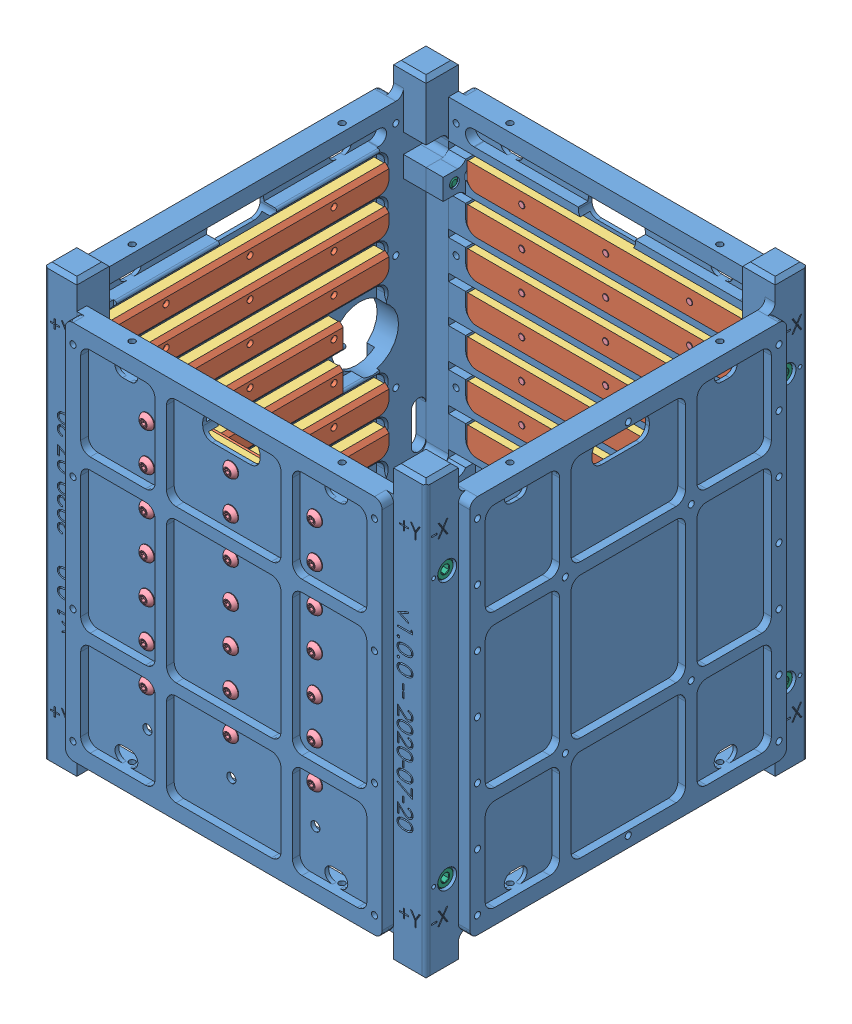
SolidWorks assembly 1UFrames, configuration Default. Lengths in mm.
Overall size (106 113.5 106).
137 component instances, 8 part files, 60 mates.
Components (placement in the parent):
- 1UFrame-2: 1UFrame [Y] at (0 0 50) x (-1 0 0) z (0 0 -1) size (83 99.5 11.5)
- 1UFrame-3: 1UFrame [+X] at (-50 0 0) x (0 0 -1) z (1 0 0) size (100 113.5 11.5)
- 1UFrame-4: 1UFrame [-X] at (50 0 0) x (0 0 1) z (-1 0 0) size (100 113.5 11.5)
- CardWedge-1: CardWedge [Default] at (0 34.95 47.1) x (-1 0 0) z (0 0 1) size (72.8 6.4 2)
- CardWedge-3: CardWedge [+Xframe] at (-47.1 34.95 0) x (0 0 -1) z (-1 0 0) size (72.8 5.9 3)
- CardWedgeTriangle-1: CardWedgeTriangle [Default] at (-50 37.35 0) x (0 -1 0) z (0 0 1) size (2 2.6 72.8)
- CardWedgeTriangle-2: CardWedgeTriangle [Default] at (0 37.85 50) x (0 -1 0) z (1 0 0) size (2 2.6 72.8)
- 90910A920_LOW-PROFILE BUTTON HEAD TORX MACHINE SCREW-1: 90910A920_LOW-PROFILE BUTTON HEAD TORX MACHINE SCREW [90910A920] at (-52.1 35.15 -22) x (0 0 1) z (-1 0 0) size (3.8 3.8 5.24)
- 90910A920_LOW-PROFILE BUTTON HEAD TORX MACHINE SCREW-73: 90910A920_LOW-PROFILE BUTTON HEAD TORX MACHINE SCREW [90910A920] at (-22 35.15 52.1) size (3.8 3.8 5.24)
- 93600A061_METRIC TYPE 316 STAINLESS STEEL DOWEL PIN-1: 93600A061_METRIC TYPE 316 STAINLESS STEEL DOWEL PIN [93600A061] at (41.5 33.95 -48) x (-1 0 0) z (0 0 -1) size (6 1.5 1.5)
- 93600A061_METRIC TYPE 316 STAINLESS STEEL DOWEL PIN-2: 93600A061_METRIC TYPE 316 STAINLESS STEEL DOWEL PIN [93600A061] at (41.5 -36.05 -48) size (6 1.5 1.5)
- 92290A060_TYPE 316 SS SOCKET HEAD CAP SCREW-1: 92290A060_TYPE 316 SS SOCKET HEAD CAP SCREW [92290A060] at (37 33.95 -44.45) x (0 0 1) z (-1 0 0) size (4.5 4.5 13.01)
- 92290A060_TYPE 316 SS SOCKET HEAD CAP SCREW-2: 92290A060_TYPE 316 SS SOCKET HEAD CAP SCREW [92290A060] at (37 -36.05 -44.45) x (0 0 1) z (-1 0 0) size (4.5 4.5 13.01)
- 84985A460_SHORT LENGTH SS LONG-NOSE SPRING PLUNGER-1: 84985A460_SHORT LENGTH SS LONG-NOSE SPRING PLUNGER [84985A46] at (45.75 -49.5999 -45.75) x (1 0 0) z (0 0 -1) size (4.81 12.73 4.27)
- 1UFrame-6: 1UFrame [Y] at (0 0 -50) size (83 99.5 11.5)
- 92290A060_TYPE 316 SS SOCKET HEAD CAP SCREW-3: 92290A060_TYPE 316 SS SOCKET HEAD CAP SCREW [92290A060] at (37 33.95 44.45) x (0 0 -1) z (-1 0 0) size (4.5 4.5 13.01)
- 93600A061_METRIC TYPE 316 STAINLESS STEEL DOWEL PIN-3: 93600A061_METRIC TYPE 316 STAINLESS STEEL DOWEL PIN [93600A061] at (41.5 33.95 48) x (-1 0 0) z (0 0 -1) size (6 1.5 1.5)
- 92290A060_TYPE 316 SS SOCKET HEAD CAP SCREW-4: 92290A060_TYPE 316 SS SOCKET HEAD CAP SCREW [92290A060] at (37 -36.05 44.45) x (0 0 -1) z (-1 0 0) size (4.5 4.5 13.01)
- 93600A061_METRIC TYPE 316 STAINLESS STEEL DOWEL PIN-4: 93600A061_METRIC TYPE 316 STAINLESS STEEL DOWEL PIN [93600A061] at (41.5 -36.05 48) size (6 1.5 1.5)
- 84985A460_SHORT LENGTH SS LONG-NOSE SPRING PLUNGER-3: 84985A460_SHORT LENGTH SS LONG-NOSE SPRING PLUNGER [84985A46] at (45.75 -49.5999 45.6569) x (1 0 0) z (0 0 -1) size (4.81 12.73 4.27)
- 92290A060_TYPE 316 SS SOCKET HEAD CAP SCREW-5: 92290A060_TYPE 316 SS SOCKET HEAD CAP SCREW [92290A060] at (-37 33.95 -44.45) x (0 0 1) z (1 0 0) size (4.5 4.5 13.01)
- 93600A061_METRIC TYPE 316 STAINLESS STEEL DOWEL PIN-5: 93600A061_METRIC TYPE 316 STAINLESS STEEL DOWEL PIN [93600A061] at (-41.5 33.95 -48) size (6 1.5 1.5)
- 92290A060_TYPE 316 SS SOCKET HEAD CAP SCREW-6: 92290A060_TYPE 316 SS SOCKET HEAD CAP SCREW [92290A060] at (-37 -36.05 -44.45) x (0 0 1) z (1 0 0) size (4.5 4.5 13.01)
- 93600A061_METRIC TYPE 316 STAINLESS STEEL DOWEL PIN-6: 93600A061_METRIC TYPE 316 STAINLESS STEEL DOWEL PIN [93600A061] at (-41.5 -36.05 -48) x (-1 0 0) z (0 0 -1) size (6 1.5 1.5)
- 84985A460_SHORT LENGTH SS LONG-NOSE SPRING PLUNGER-4: 84985A460_SHORT LENGTH SS LONG-NOSE SPRING PLUNGER [84985A46] at (-45.75 -49.5999 -45.6569) x (-1 0 0) z (0 0 1) size (4.81 12.73 4.27)
- 92290A060_TYPE 316 SS SOCKET HEAD CAP SCREW-7: 92290A060_TYPE 316 SS SOCKET HEAD CAP SCREW [92290A060] at (-37 33.95 44.45) x (0 0 -1) z (1 0 0) size (4.5 4.5 13.01)
- 93600A061_METRIC TYPE 316 STAINLESS STEEL DOWEL PIN-7: 93600A061_METRIC TYPE 316 STAINLESS STEEL DOWEL PIN [93600A061] at (-41.5 33.95 48) size (6 1.5 1.5)
- 92290A060_TYPE 316 SS SOCKET HEAD CAP SCREW-8: 92290A060_TYPE 316 SS SOCKET HEAD CAP SCREW [92290A060] at (-37 -36.05 44.45) x (0 0 -1) z (1 0 0) size (4.5 4.5 13.01)
- 93600A061_METRIC TYPE 316 STAINLESS STEEL DOWEL PIN-8: 93600A061_METRIC TYPE 316 STAINLESS STEEL DOWEL PIN [93600A061] at (-41.5 -36.05 48) x (-1 0 0) z (0 0 -1) size (6 1.5 1.5)
- 84985A460_SHORT LENGTH SS LONG-NOSE SPRING PLUNGER-5: 84985A460_SHORT LENGTH SS LONG-NOSE SPRING PLUNGER [84985A46] at (-45.75 -49.5999 45.75) x (-1 0 0) z (0 0 1) size (4.81 12.73 4.27)
- CardWedgeTriangle-3: CardWedgeTriangle [Default] at (0 27.85 50) x (0 -1 0) z (1 0 0) size (2 2.6 72.8)
- CardWedgeTriangle-4: CardWedgeTriangle [Default] at (0 17.85 50) x (0 -1 0) z (1 0 0) size (2 2.6 72.8)
- CardWedgeTriangle-5: CardWedgeTriangle [Default] at (0 7.85 50) x (0 -1 0) z (1 0 0) size (2 2.6 72.8)
- CardWedgeTriangle-6: CardWedgeTriangle [Default] at (0 -2.15 50) x (0 -1 0) z (1 0 0) size (2 2.6 72.8)
- CardWedgeTriangle-7: CardWedgeTriangle [Default] at (0 -12.15 50) x (0 -1 0) z (1 0 0) size (2 2.6 72.8)
- CardWedgeTriangle-8: CardWedgeTriangle [Default] at (0 -22.15 50) x (0 -1 0) z (1 0 0) size (2 2.6 72.8)
- CardWedge-4: CardWedge [Default] at (0 24.95 47.1) x (-1 0 0) z (0 0 1) size (72.8 6.4 2)
- CardWedge-5: CardWedge [Default] at (0 14.95 47.1) x (-1 0 0) z (0 0 1) size (72.8 6.4 2)
- CardWedge-6: CardWedge [Default] at (0 4.95 47.1) x (-1 0 0) z (0 0 1) size (72.8 6.4 2)
- CardWedge-7: CardWedge [Default] at (0 -5.05 47.1) x (-1 0 0) z (0 0 1) size (72.8 6.4 2)
- CardWedge-8: CardWedge [Default] at (0 -15.05 47.1) x (-1 0 0) z (0 0 1) size (72.8 6.4 2)
- CardWedge-9: CardWedge [Default] at (0 -25.05 47.1) x (-1 0 0) z (0 0 1) size (72.8 6.4 2)
- 90910A920_LOW-PROFILE BUTTON HEAD TORX MACHINE SCREW-74: 90910A920_LOW-PROFILE BUTTON HEAD TORX MACHINE SCREW [90910A920] at (-22 25.15 52.1) size (3.8 3.8 5.24)
- 90910A920_LOW-PROFILE BUTTON HEAD TORX MACHINE SCREW-75: 90910A920_LOW-PROFILE BUTTON HEAD TORX MACHINE SCREW [90910A920] at (-22 15.15 52.1) size (3.8 3.8 5.24)
- 90910A920_LOW-PROFILE BUTTON HEAD TORX MACHINE SCREW-76: 90910A920_LOW-PROFILE BUTTON HEAD TORX MACHINE SCREW [90910A920] at (-22 5.15 52.1) size (3.8 3.8 5.24)
- 90910A920_LOW-PROFILE BUTTON HEAD TORX MACHINE SCREW-77: 90910A920_LOW-PROFILE BUTTON HEAD TORX MACHINE SCREW [90910A920] at (-22 -4.85 52.1) size (3.8 3.8 5.24)
- 90910A920_LOW-PROFILE BUTTON HEAD TORX MACHINE SCREW-78: 90910A920_LOW-PROFILE BUTTON HEAD TORX MACHINE SCREW [90910A920] at (-22 -14.85 52.1) size (3.8 3.8 5.24)
- 90910A920_LOW-PROFILE BUTTON HEAD TORX MACHINE SCREW-79: 90910A920_LOW-PROFILE BUTTON HEAD TORX MACHINE SCREW [90910A920] at (-22 -24.85 52.1) size (3.8 3.8 5.24)
- 90910A920_LOW-PROFILE BUTTON HEAD TORX MACHINE SCREW-81: 90910A920_LOW-PROFILE BUTTON HEAD TORX MACHINE SCREW [90910A920] at (0 35.15 52.1) size (3.8 3.8 5.24)
- 90910A920_LOW-PROFILE BUTTON HEAD TORX MACHINE SCREW-82: 90910A920_LOW-PROFILE BUTTON HEAD TORX MACHINE SCREW [90910A920] at (0 25.15 52.1) size (3.8 3.8 5.24)
- 90910A920_LOW-PROFILE BUTTON HEAD TORX MACHINE SCREW-83: 90910A920_LOW-PROFILE BUTTON HEAD TORX MACHINE SCREW [90910A920] at (0 15.15 52.1) size (3.8 3.8 5.24)
- 90910A920_LOW-PROFILE BUTTON HEAD TORX MACHINE SCREW-84: 90910A920_LOW-PROFILE BUTTON HEAD TORX MACHINE SCREW [90910A920] at (0 5.15 52.1) size (3.8 3.8 5.24)
- 90910A920_LOW-PROFILE BUTTON HEAD TORX MACHINE SCREW-85: 90910A920_LOW-PROFILE BUTTON HEAD TORX MACHINE SCREW [90910A920] at (0 -4.85 52.1) size (3.8 3.8 5.24)
- 90910A920_LOW-PROFILE BUTTON HEAD TORX MACHINE SCREW-86: 90910A920_LOW-PROFILE BUTTON HEAD TORX MACHINE SCREW [90910A920] at (0 -14.85 52.1) size (3.8 3.8 5.24)
- 90910A920_LOW-PROFILE BUTTON HEAD TORX MACHINE SCREW-87: 90910A920_LOW-PROFILE BUTTON HEAD TORX MACHINE SCREW [90910A920] at (0 -24.85 52.1) size (3.8 3.8 5.24)
- 90910A920_LOW-PROFILE BUTTON HEAD TORX MACHINE SCREW-89: 90910A920_LOW-PROFILE BUTTON HEAD TORX MACHINE SCREW [90910A920] at (22 35.15 52.1) size (3.8 3.8 5.24)
- 90910A920_LOW-PROFILE BUTTON HEAD TORX MACHINE SCREW-90: 90910A920_LOW-PROFILE BUTTON HEAD TORX MACHINE SCREW [90910A920] at (22 25.15 52.1) size (3.8 3.8 5.24)
- 90910A920_LOW-PROFILE BUTTON HEAD TORX MACHINE SCREW-91: 90910A920_LOW-PROFILE BUTTON HEAD TORX MACHINE SCREW [90910A920] at (22 15.15 52.1) size (3.8 3.8 5.24)
- 90910A920_LOW-PROFILE BUTTON HEAD TORX MACHINE SCREW-92: 90910A920_LOW-PROFILE BUTTON HEAD TORX MACHINE SCREW [90910A920] at (22 5.15 52.1) size (3.8 3.8 5.24)
- 90910A920_LOW-PROFILE BUTTON HEAD TORX MACHINE SCREW-93: 90910A920_LOW-PROFILE BUTTON HEAD TORX MACHINE SCREW [90910A920] at (22 -4.85 52.1) size (3.8 3.8 5.24)
- 90910A920_LOW-PROFILE BUTTON HEAD TORX MACHINE SCREW-94: 90910A920_LOW-PROFILE BUTTON HEAD TORX MACHINE SCREW [90910A920] at (22 -14.85 52.1) size (3.8 3.8 5.24)
- 90910A920_LOW-PROFILE BUTTON HEAD TORX MACHINE SCREW-95: 90910A920_LOW-PROFILE BUTTON HEAD TORX MACHINE SCREW [90910A920] at (22 -24.85 52.1) size (3.8 3.8 5.24)
- CardWedgeTriangle-10: CardWedgeTriangle [Default] at (0 37.85 -50) x (0 -1 0) z (-1 0 0) size (2 2.6 72.8)
- CardWedge-11: CardWedge [Default] at (0 34.95 -47.1) x (1 0 0) z (0 0 -1) size (72.8 6.4 2)
- CardWedgeTriangle-11: CardWedgeTriangle [Default] at (0 27.85 -50) x (0 -1 0) z (-1 0 0) size (2 2.6 72.8)
- CardWedgeTriangle-12: CardWedgeTriangle [Default] at (0 17.85 -50) x (0 -1 0) z (-1 0 0) size (2 2.6 72.8)
- CardWedgeTriangle-13: CardWedgeTriangle [Default] at (0 7.85 -50) x (0 -1 0) z (-1 0 0) size (2 2.6 72.8)
- CardWedgeTriangle-14: CardWedgeTriangle [Default] at (0 -2.15 -50) x (0 -1 0) z (-1 0 0) size (2 2.6 72.8)
- CardWedgeTriangle-15: CardWedgeTriangle [Default] at (0 -12.15 -50) x (0 -1 0) z (-1 0 0) size (2 2.6 72.8)
- CardWedgeTriangle-16: CardWedgeTriangle [Default] at (0 -22.15 -50) x (0 -1 0) z (-1 0 0) size (2 2.6 72.8)
- CardWedge-12: CardWedge [Default] at (0 24.95 -47.1) x (1 0 0) z (0 0 -1) size (72.8 6.4 2)
- CardWedge-13: CardWedge [Default] at (0 14.95 -47.1) x (1 0 0) z (0 0 -1) size (72.8 6.4 2)
- CardWedge-14: CardWedge [Default] at (0 4.95 -47.1) x (1 0 0) z (0 0 -1) size (72.8 6.4 2)
- CardWedge-15: CardWedge [Default] at (0 -5.05 -47.1) x (1 0 0) z (0 0 -1) size (72.8 6.4 2)
- CardWedge-16: CardWedge [Default] at (0 -15.05 -47.1) x (1 0 0) z (0 0 -1) size (72.8 6.4 2)
- CardWedge-17: CardWedge [Default] at (0 -25.05 -47.1) x (1 0 0) z (0 0 -1) size (72.8 6.4 2)
- 90910A920_LOW-PROFILE BUTTON HEAD TORX MACHINE SCREW-97: 90910A920_LOW-PROFILE BUTTON HEAD TORX MACHINE SCREW [90910A920] at (-22 35.15 -52.1) x (1 0 0) z (0 0 -1) size (3.8 3.8 5.24)
- 90910A920_LOW-PROFILE BUTTON HEAD TORX MACHINE SCREW-98: 90910A920_LOW-PROFILE BUTTON HEAD TORX MACHINE SCREW [90910A920] at (-22 25.15 -52.1) x (1 0 0) z (0 0 -1) size (3.8 3.8 5.24)
- 90910A920_LOW-PROFILE BUTTON HEAD TORX MACHINE SCREW-99: 90910A920_LOW-PROFILE BUTTON HEAD TORX MACHINE SCREW [90910A920] at (-22 15.15 -52.1) x (1 0 0) z (0 0 -1) size (3.8 3.8 5.24)
- 90910A920_LOW-PROFILE BUTTON HEAD TORX MACHINE SCREW-100: 90910A920_LOW-PROFILE BUTTON HEAD TORX MACHINE SCREW [90910A920] at (-22 5.15 -52.1) x (1 0 0) z (0 0 -1) size (3.8 3.8 5.24)
- 90910A920_LOW-PROFILE BUTTON HEAD TORX MACHINE SCREW-101: 90910A920_LOW-PROFILE BUTTON HEAD TORX MACHINE SCREW [90910A920] at (-22 -4.85 -52.1) x (1 0 0) z (0 0 -1) size (3.8 3.8 5.24)
- 90910A920_LOW-PROFILE BUTTON HEAD TORX MACHINE SCREW-102: 90910A920_LOW-PROFILE BUTTON HEAD TORX MACHINE SCREW [90910A920] at (-22 -14.85 -52.1) x (1 0 0) z (0 0 -1) size (3.8 3.8 5.24)
- 90910A920_LOW-PROFILE BUTTON HEAD TORX MACHINE SCREW-103: 90910A920_LOW-PROFILE BUTTON HEAD TORX MACHINE SCREW [90910A920] at (-22 -24.85 -52.1) x (1 0 0) z (0 0 -1) size (3.8 3.8 5.24)
- 90910A920_LOW-PROFILE BUTTON HEAD TORX MACHINE SCREW-104: 90910A920_LOW-PROFILE BUTTON HEAD TORX MACHINE SCREW [90910A920] at (0 35.15 -52.1) x (1 0 0) z (0 0 -1) size (3.8 3.8 5.24)
- 90910A920_LOW-PROFILE BUTTON HEAD TORX MACHINE SCREW-105: 90910A920_LOW-PROFILE BUTTON HEAD TORX MACHINE SCREW [90910A920] at (0 25.15 -52.1) x (1 0 0) z (0 0 -1) size (3.8 3.8 5.24)
- 90910A920_LOW-PROFILE BUTTON HEAD TORX MACHINE SCREW-106: 90910A920_LOW-PROFILE BUTTON HEAD TORX MACHINE SCREW [90910A920] at (0 15.15 -52.1) x (1 0 0) z (0 0 -1) size (3.8 3.8 5.24)
- 90910A920_LOW-PROFILE BUTTON HEAD TORX MACHINE SCREW-107: 90910A920_LOW-PROFILE BUTTON HEAD TORX MACHINE SCREW [90910A920] at (0 5.15 -52.1) x (1 0 0) z (0 0 -1) size (3.8 3.8 5.24)
- 90910A920_LOW-PROFILE BUTTON HEAD TORX MACHINE SCREW-108: 90910A920_LOW-PROFILE BUTTON HEAD TORX MACHINE SCREW [90910A920] at (0 -4.85 -52.1) x (1 0 0) z (0 0 -1) size (3.8 3.8 5.24)
- 90910A920_LOW-PROFILE BUTTON HEAD TORX MACHINE SCREW-109: 90910A920_LOW-PROFILE BUTTON HEAD TORX MACHINE SCREW [90910A920] at (0 -14.85 -52.1) x (1 0 0) z (0 0 -1) size (3.8 3.8 5.24)
- 90910A920_LOW-PROFILE BUTTON HEAD TORX MACHINE SCREW-110: 90910A920_LOW-PROFILE BUTTON HEAD TORX MACHINE SCREW [90910A920] at (0 -24.85 -52.1) x (1 0 0) z (0 0 -1) size (3.8 3.8 5.24)
- 90910A920_LOW-PROFILE BUTTON HEAD TORX MACHINE SCREW-111: 90910A920_LOW-PROFILE BUTTON HEAD TORX MACHINE SCREW [90910A920] at (22 35.15 -52.1) x (1 0 0) z (0 0 -1) size (3.8 3.8 5.24)
- 90910A920_LOW-PROFILE BUTTON HEAD TORX MACHINE SCREW-112: 90910A920_LOW-PROFILE BUTTON HEAD TORX MACHINE SCREW [90910A920] at (22 25.15 -52.1) x (1 0 0) z (0 0 -1) size (3.8 3.8 5.24)
- 90910A920_LOW-PROFILE BUTTON HEAD TORX MACHINE SCREW-113: 90910A920_LOW-PROFILE BUTTON HEAD TORX MACHINE SCREW [90910A920] at (22 15.15 -52.1) x (1 0 0) z (0 0 -1) size (3.8 3.8 5.24)
- 90910A920_LOW-PROFILE BUTTON HEAD TORX MACHINE SCREW-114: 90910A920_LOW-PROFILE BUTTON HEAD TORX MACHINE SCREW [90910A920] at (22 5.15 -52.1) x (1 0 0) z (0 0 -1) size (3.8 3.8 5.24)
- 90910A920_LOW-PROFILE BUTTON HEAD TORX MACHINE SCREW-115: 90910A920_LOW-PROFILE BUTTON HEAD TORX MACHINE SCREW [90910A920] at (22 -4.85 -52.1) x (1 0 0) z (0 0 -1) size (3.8 3.8 5.24)
- 90910A920_LOW-PROFILE BUTTON HEAD TORX MACHINE SCREW-116: 90910A920_LOW-PROFILE BUTTON HEAD TORX MACHINE SCREW [90910A920] at (22 -14.85 -52.1) x (1 0 0) z (0 0 -1) size (3.8 3.8 5.24)
- 90910A920_LOW-PROFILE BUTTON HEAD TORX MACHINE SCREW-117: 90910A920_LOW-PROFILE BUTTON HEAD TORX MACHINE SCREW [90910A920] at (22 -24.85 -52.1) x (1 0 0) z (0 0 -1) size (3.8 3.8 5.24)
- CardWedge-19: CardWedge [+Xframe] at (-47.1 24.95 0) x (0 0 -1) z (-1 0 0) size (72.8 5.9 3)
- CardWedge-20: CardWedge [+Xframe] at (-47.1 14.95 0) x (0 0 -1) z (-1 0 0) size (72.8 5.9 3)
- CardWedge-23: CardWedge [+Xframe] at (-47.1 -15.05 0) x (0 0 -1) z (-1 0 0) size (72.8 5.9 3)
- CardWedge-24: CardWedge [+Xframe] at (-47.1 -25.05 0) x (0 0 -1) z (-1 0 0) size (72.8 5.9 3)
- CardWedgeTriangle-18: CardWedgeTriangle [Default] at (-50 27.35 0) x (0 -1 0) z (0 0 1) size (2 2.6 72.8)
- CardWedgeTriangle-19: CardWedgeTriangle [Default] at (-50 17.35 0) x (0 -1 0) z (0 0 1) size (2 2.6 72.8)
- CardWedgeTriangle-22: CardWedgeTriangle [Default] at (-50 -12.65 0) x (0 -1 0) z (0 0 1) size (2 2.6 72.8)
- CardWedgeTriangle-23: CardWedgeTriangle [Default] at (-50 -22.65 0) x (0 -1 0) z (0 0 1) size (2 2.6 72.8)
- 90910A920_LOW-PROFILE BUTTON HEAD TORX MACHINE SCREW-50: 90910A920_LOW-PROFILE BUTTON HEAD TORX MACHINE SCREW [90910A920] at (-52.1 25.15 -22) x (0 0 1) z (-1 0 0) size (3.8 3.8 5.24)
- 90910A920_LOW-PROFILE BUTTON HEAD TORX MACHINE SCREW-51: 90910A920_LOW-PROFILE BUTTON HEAD TORX MACHINE SCREW [90910A920] at (-52.1 15.15 -22) x (0 0 1) z (-1 0 0) size (3.8 3.8 5.24)
- 90910A920_LOW-PROFILE BUTTON HEAD TORX MACHINE SCREW-52: 90910A920_LOW-PROFILE BUTTON HEAD TORX MACHINE SCREW [90910A920] at (-52.1 5.15 -22) x (0 0 1) z (-1 0 0) size (3.8 3.8 5.24)
- 90910A920_LOW-PROFILE BUTTON HEAD TORX MACHINE SCREW-53: 90910A920_LOW-PROFILE BUTTON HEAD TORX MACHINE SCREW [90910A920] at (-52.1 -4.85 -22) x (0 0 1) z (-1 0 0) size (3.8 3.8 5.24)
- 90910A920_LOW-PROFILE BUTTON HEAD TORX MACHINE SCREW-54: 90910A920_LOW-PROFILE BUTTON HEAD TORX MACHINE SCREW [90910A920] at (-52.1 -14.85 -22) x (0 0 1) z (-1 0 0) size (3.8 3.8 5.24)
- 90910A920_LOW-PROFILE BUTTON HEAD TORX MACHINE SCREW-55: 90910A920_LOW-PROFILE BUTTON HEAD TORX MACHINE SCREW [90910A920] at (-52.1 -24.85 -22) x (0 0 1) z (-1 0 0) size (3.8 3.8 5.24)
- 90910A920_LOW-PROFILE BUTTON HEAD TORX MACHINE SCREW-57: 90910A920_LOW-PROFILE BUTTON HEAD TORX MACHINE SCREW [90910A920] at (-52.1 35.15 0) x (0 0 1) z (-1 0 0) size (3.8 3.8 5.24)
- 90910A920_LOW-PROFILE BUTTON HEAD TORX MACHINE SCREW-58: 90910A920_LOW-PROFILE BUTTON HEAD TORX MACHINE SCREW [90910A920] at (-52.1 25.15 0) x (0 0 1) z (-1 0 0) size (3.8 3.8 5.24)
- 90910A920_LOW-PROFILE BUTTON HEAD TORX MACHINE SCREW-59: 90910A920_LOW-PROFILE BUTTON HEAD TORX MACHINE SCREW [90910A920] at (-52.1 15.15 0) x (0 0 1) z (-1 0 0) size (3.8 3.8 5.24)
- 90910A920_LOW-PROFILE BUTTON HEAD TORX MACHINE SCREW-60: 90910A920_LOW-PROFILE BUTTON HEAD TORX MACHINE SCREW [90910A920] at (-52.1 5.15 0) x (0 0 1) z (-1 0 0) size (3.8 3.8 5.24)
- 90910A920_LOW-PROFILE BUTTON HEAD TORX MACHINE SCREW-61: 90910A920_LOW-PROFILE BUTTON HEAD TORX MACHINE SCREW [90910A920] at (-52.1 -4.85 0) x (0 0 1) z (-1 0 0) size (3.8 3.8 5.24)
- 90910A920_LOW-PROFILE BUTTON HEAD TORX MACHINE SCREW-62: 90910A920_LOW-PROFILE BUTTON HEAD TORX MACHINE SCREW [90910A920] at (-52.1 -14.85 0) x (0 0 1) z (-1 0 0) size (3.8 3.8 5.24)
- 90910A920_LOW-PROFILE BUTTON HEAD TORX MACHINE SCREW-63: 90910A920_LOW-PROFILE BUTTON HEAD TORX MACHINE SCREW [90910A920] at (-52.1 -24.85 0) x (0 0 1) z (-1 0 0) size (3.8 3.8 5.24)
- 90910A920_LOW-PROFILE BUTTON HEAD TORX MACHINE SCREW-65: 90910A920_LOW-PROFILE BUTTON HEAD TORX MACHINE SCREW [90910A920] at (-52.1 35.15 22) x (0 0 1) z (-1 0 0) size (3.8 3.8 5.24)
- 90910A920_LOW-PROFILE BUTTON HEAD TORX MACHINE SCREW-66: 90910A920_LOW-PROFILE BUTTON HEAD TORX MACHINE SCREW [90910A920] at (-52.1 25.15 22) x (0 0 1) z (-1 0 0) size (3.8 3.8 5.24)
- 90910A920_LOW-PROFILE BUTTON HEAD TORX MACHINE SCREW-67: 90910A920_LOW-PROFILE BUTTON HEAD TORX MACHINE SCREW [90910A920] at (-52.1 15.15 22) x (0 0 1) z (-1 0 0) size (3.8 3.8 5.24)
- 90910A920_LOW-PROFILE BUTTON HEAD TORX MACHINE SCREW-68: 90910A920_LOW-PROFILE BUTTON HEAD TORX MACHINE SCREW [90910A920] at (-52.1 5.15 22) x (0 0 1) z (-1 0 0) size (3.8 3.8 5.24)
- 90910A920_LOW-PROFILE BUTTON HEAD TORX MACHINE SCREW-69: 90910A920_LOW-PROFILE BUTTON HEAD TORX MACHINE SCREW [90910A920] at (-52.1 -4.85 22) x (0 0 1) z (-1 0 0) size (3.8 3.8 5.24)
- 90910A920_LOW-PROFILE BUTTON HEAD TORX MACHINE SCREW-70: 90910A920_LOW-PROFILE BUTTON HEAD TORX MACHINE SCREW [90910A920] at (-52.1 -14.85 22) x (0 0 1) z (-1 0 0) size (3.8 3.8 5.24)
- 90910A920_LOW-PROFILE BUTTON HEAD TORX MACHINE SCREW-71: 90910A920_LOW-PROFILE BUTTON HEAD TORX MACHINE SCREW [90910A920] at (-52.1 -24.85 22) x (0 0 1) z (-1 0 0) size (3.8 3.8 5.24)
- CardWedgeTriangle-25: CardWedgeTriangle [StarTrackerWedge] at (-50 7.35 0) x (0 -1 0) z (0 0 1) size (2 2.6 60.8)
- CardWedge-26: CardWedge [startrackerwedge] at (-47.1 4.95 0) x (0 0 -1) z (-1 0 0) size (60.8 5.9 3)
- CardWedgeTriangle-26: CardWedgeTriangle [StarTrackerWedge] at (-50 -2.65 0) x (0 -1 0) z (0 0 1) size (2 2.6 60.8)
- CardWedge-27: CardWedge [startrackerwedge] at (-47.1 -5.05 0) x (0 0 -1) z (-1 0 0) size (60.8 5.9 3)
- 91630A221_SCREW-LOCK HELICAL INSERTS WITHOUT PRONG-1: 91630A221_SCREW-LOCK HELICAL INSERTS WITHOUT PRONG [91630A221] at (41.5 33.95 -44.45) x (0 1 0) z (0 0 1) size (3.78 2.46 4.27)
- 91630A221_SCREW-LOCK HELICAL INSERTS WITHOUT PRONG-2: 91630A221_SCREW-LOCK HELICAL INSERTS WITHOUT PRONG [91630A221] at (41.5 -36.05 -44.45) x (0 1 0) z (0 0 1) size (3.78 2.46 4.27)
- 91630A221_SCREW-LOCK HELICAL INSERTS WITHOUT PRONG-3: 91630A221_SCREW-LOCK HELICAL INSERTS WITHOUT PRONG [91630A221] at (41.5 33.95 44.45) x (0 1 0) z (0 0 1) size (3.78 2.46 4.27)
- 91630A221_SCREW-LOCK HELICAL INSERTS WITHOUT PRONG-4: 91630A221_SCREW-LOCK HELICAL INSERTS WITHOUT PRONG [91630A221] at (41.5 -36.05 44.45) x (0 1 0) z (0 0 1) size (3.78 2.46 4.27)
- 91630A221_SCREW-LOCK HELICAL INSERTS WITHOUT PRONG-5: 91630A221_SCREW-LOCK HELICAL INSERTS WITHOUT PRONG [91630A221] at (-41.5 33.95 44.45) x (0 1 0) z (0 0 -1) size (3.78 2.46 4.27)
- 91630A221_SCREW-LOCK HELICAL INSERTS WITHOUT PRONG-6: 91630A221_SCREW-LOCK HELICAL INSERTS WITHOUT PRONG [91630A221] at (-41.5 -36.05 44.45) x (0 1 0) z (0 0 -1) size (3.78 2.46 4.27)
- 91630A221_SCREW-LOCK HELICAL INSERTS WITHOUT PRONG-7: 91630A221_SCREW-LOCK HELICAL INSERTS WITHOUT PRONG [91630A221] at (-41.5 -36.05 -44.45) x (0 1 0) z (0 0 -1) size (3.78 2.46 4.27)
- 91630A221_SCREW-LOCK HELICAL INSERTS WITHOUT PRONG-8: 91630A221_SCREW-LOCK HELICAL INSERTS WITHOUT PRONG [91630A221] at (-41.5 33.95 -44.45) x (0 1 0) z (0 0 -1) size (3.78 2.46 4.27)
Mates (geometry in assembly coordinates):
- Coincident2: coincident anti-aligned: plane of 1UFrame-2 through (41.5 0 47.4) normal (1 0 0); plane of 1UFrame-4 through (41.5 0 0) normal (-1 0 0)
- Concentric2: concentric aligned: cylinder of 1UFrame-2 through (41.5 33.95 44.45) axis (1 0 0) radius 1.275; cylinder of 1UFrame-4 through (47 33.95 44.45) axis (1 0 0) radius 1.45
- Coincident30: coincident aligned: plane of 1UFrame-4 through (50 0 0) normal (0 0 1)
- Parallel2: parallel anti-aligned: plane of 1UFrame-2 through (0 0 50) normal (0 0 -1)
- Coincident6: coincident anti-aligned: plane of 1UFrame-2 through (-41.5 0 47.4) normal (-1 0 0); plane of 1UFrame-3 through (-41.5 0 0) normal (1 0 0)
- Concentric3: concentric aligned: cylinder of 1UFrame-2 through (-41.5 33.95 44.45) axis (-1 0 0) radius 1.275; cylinder of 1UFrame-3 through (-47 33.95 44.45) axis (-1 0 0) radius 1.45
- Coincident7: coincident aligned: plane of 1UFrame-2 through (0 0 50) normal (0 1 0)
- Coincident8: coincident anti-aligned: plane of 1UFrame-2 through (0 0 50) normal (-1 0 0)
- Coincident9: coincident anti-aligned: plane of 1UFrame-3 through (-50 0 0) normal (0 0 -1)
- Coincident10: coincident aligned: plane of 1UFrame-5 through (0 0 -50) normal (0 1 0)
- Coincident11: coincident aligned: plane of 1UFrame-5 through (0 0 -50) normal (1 0 0)
- Concentric4: concentric aligned: cylinder of 1UFrame-3 through (-47 33.95 -44.45) axis (-1 0 0) radius 1.45; cylinder of 1UFrame-5 through (-41.5 33.95 -44.45) axis (-1 0 0) radius 1.275
- Coincident12: coincident anti-aligned: plane of 1UFrame-3 through (26.627 31.75 37) normal (0 1 0); plane of CardWedge-3 through (-49.1 31.75 -36.4) normal (0 -1 0)
- Concentric5: concentric aligned: cylinder of 1UFrame-3 through (-51 35.15 0) axis (-1 0 0) radius 1.2; cylinder of CardWedge-3 through (-49.1 35.15 0) axis (-1 0 0) radius 0.8
- Coincident14: coincident anti-aligned: plane of 1UFrame-3 through (-50 0 0) normal (1 0 0); plane of CardWedgeTriangle-1 through (-50 37.35 -36.4) normal (-1 0 0)
- Coincident15: coincident anti-aligned: plane of CardWedgeTriangle-1 through (-48.7 36.05 -36.4) normal (0.707107 -0.707107 0); plane of CardWedge-3 through (-47.1 37.65 -39.6016) normal (-0.707107 0.707107 0)
- Coincident17: coincident aligned: plane of CardWedgeTriangle-1 through (-50 37.35 36.4) normal (0 0 1); plane of CardWedge-3 through (-47.1 34.95 36.4) normal (0 0 1)
- Coincident18: coincident anti-aligned: plane of 1UFrame-3 through (-51 0 0) normal (-1 0 0); plane of 92095A104_BUTTON HEAD HEX DRIVE SCREW-3 through (-51 35.15 -20.1) normal (1 0 0)
- Concentric7: concentric aligned: circle of 1UFrame-3; circle of 92095A104_BUTTON HEAD HEX DRIVE SCREW-3
- Parallel4: parallel anti-aligned: plane of 92095A104_BUTTON HEAD HEX DRIVE SCREW-3 through (-51.9 35.15 -22) normal (0 0 -1)
- Coincident20: coincident anti-aligned: plane of 1UFrame-2 through (37 31.75 -26.627) normal (0 1 0); plane of CardWedge-1 through (-36.4 31.75 49.1) normal (0 -1 0)
- Concentric8: concentric aligned: cylinder of 1UFrame-2 through (0 35.15 51) axis (0 0 1) radius 1.2; cylinder of CardWedge-1 through (0 35.15 49.1) axis (0 0 1) radius 0.8
- Coincident24: coincident anti-aligned: plane of 1UFrame-2 through (0 0 50) normal (0 0 -1); plane of CardWedgeTriangle-2 through (-36.4 37.85 50) normal (0 0 1)
- Coincident25: coincident anti-aligned: plane of CardWedge-1 through (-36.4 38.15 47.1) normal (0 0.707107 0.707107); plane of CardWedgeTriangle-2 through (-36.4 36.55 48.7) normal (0 -0.707107 -0.707107)
- Concentric11: concentric aligned: cylinder of 1UFrame-3 through (-51 35.15 0) axis (-1 0 0) radius 1.2; cylinder of CardWedgeTriangle-1 through (-45.8444 35.15 0) axis (-1 0 0) radius 1.1
- Coincident26: coincident aligned: plane of 1UFrame-2 through (41.5 37.85 50) normal (0 1 0); plane of CardWedgeTriangle-2 through (-36.4 37.85 50) normal (0 1 0)
- Coincident31: coincident anti-aligned: plane of 1UFrame-3 through (-51 0 0) normal (-1 0 0); plane of 90910A920_LOW-PROFILE BUTTON HEAD TORX MACHINE SCREW-1 through (-51 33.25 -22) normal (1 0 0)
- Concentric14: concentric aligned: cylinder of 1UFrame-3 through (-51 35.15 -22) axis (-1 0 0) radius 1.2; cylinder of 90910A920_LOW-PROFILE BUTTON HEAD TORX MACHINE SCREW-1 through (-52.1 35.15 -22) axis (-1 0 0) radius 1.9
- Coincident32: coincident anti-aligned: plane of 1UFrame-2 through (0 0 51) normal (0 0 1); plane of 90910A920_LOW-PROFILE BUTTON HEAD TORX MACHINE SCREW-73 through (-22 33.25 51) normal (0 0 -1)
- Concentric15: concentric aligned: cylinder of 1UFrame-2 through (-22 35.15 51) axis (0 0 1) radius 1.2; cylinder of 90910A920_LOW-PROFILE BUTTON HEAD TORX MACHINE SCREW-73 through (-22 35.15 52.1) axis (0 0 1) radius 1.9
- Parallel5: parallel aligned: plane of 90910A920_LOW-PROFILE BUTTON HEAD TORX MACHINE SCREW-1 through (-52.1 35.15 -22) normal (0 0 1)
- Parallel6: parallel aligned: plane of 90910A920_LOW-PROFILE BUTTON HEAD TORX MACHINE SCREW-73 through (-22 35.15 52.1) normal (1 0 0)
- Concentric18: concentric aligned: cone of 1UFrame-4 through (44.5 33.95 -48) axis (1 0 0); cone of 93600A061_METRIC TYPE 316 STAINLESS STEEL DOWEL PIN-1 through (44.2 33.95 -48) axis (1 0 0)
- Coincident36: coincident anti-aligned: circle of 1UFrame-4; plane of 93600A061_METRIC TYPE 316 STAINLESS STEEL DOWEL PIN-1 through (44.5 33.95 -48) normal (1 0 0)
- Concentric19: concentric anti-aligned: cylinder of 1UFrame-4 through (41.5 -36.05 -48) axis (-1 0 0) radius 0.75; cylinder of 93600A061_METRIC TYPE 316 STAINLESS STEEL DOWEL PIN-2 through (38.8 -36.05 -48) axis (1 0 0) radius 0.75
- Coincident37: coincident anti-aligned: circle of 1UFrame-4; plane of 93600A061_METRIC TYPE 316 STAINLESS STEEL DOWEL PIN-2 through (44.5 -36.05 -48) normal (1 0 0)
- Parallel8: parallel anti-aligned: plane of 93600A061_METRIC TYPE 316 STAINLESS STEEL DOWEL PIN-1 through (41.5 33.95 -48) normal (0 0 -1)
- Parallel9: parallel aligned: plane of 93600A061_METRIC TYPE 316 STAINLESS STEEL DOWEL PIN-2 through (41.5 -36.05 -48) normal (0 0 1)
- Coincident40: coincident aligned: plane of CardWedge-1 through (36.4 34.95 47.1) normal (1 0 0); plane of CardWedgeTriangle-2 through (36.4 37.85 50) normal (1 0 0)
- Coincident41: coincident anti-aligned: plane of 1UFrame-4 through (47 33.95 -44.45) normal (1 0 0); plane of 92290A060_TYPE 316 SS SOCKET HEAD CAP SCREW-1 through (47 33.95 -44.45) normal (-1 0 0)
- Coincident42: coincident anti-aligned: plane of 1UFrame-4 through (47 -36.05 -44.45) normal (1 0 0); plane of 92290A060_TYPE 316 SS SOCKET HEAD CAP SCREW-2 through (47 -36.05 -44.45) normal (-1 0 0)
- Concentric20: concentric anti-aligned: cylinder of 1UFrame-4 through (47 -36.05 -44.45) axis (1 0 0) radius 2.5; cylinder of 92290A060_TYPE 316 SS SOCKET HEAD CAP SCREW-2 through (49.5 -36.05 -44.45) axis (-1 0 0) radius 2.25
- Concentric21: concentric anti-aligned: cylinder of 1UFrame-4 through (47 33.95 -44.45) axis (1 0 0) radius 2.5; cylinder of 92290A060_TYPE 316 SS SOCKET HEAD CAP SCREW-1 through (49.5 33.95 -44.45) axis (-1 0 0) radius 2.25
- Parallel10: parallel aligned: plane of 92290A060_TYPE 316 SS SOCKET HEAD CAP SCREW-1 through (37 33.95 -44.45) normal (0 0 1)
- Parallel11: parallel aligned: plane of 92290A060_TYPE 316 SS SOCKET HEAD CAP SCREW-2 through (37 -36.05 -44.45) normal (0 0 1)
- Parallel12: parallel anti-aligned: plane of 84985A460_SHORT LENGTH SS LONG-NOSE SPRING PLUNGER-1 through (45.75 -49.5999 -45.75) normal (0 0 -1)
- Coincident49: coincident anti-aligned: circle of 1UFrame-4; plane of 84985A460_SHORT LENGTH SS LONG-NOSE SPRING PLUNGER-1 through (45.75 -44.05 -45.75) normal (0 1 0)
- Concentric23: concentric aligned: cylinder of 1UFrame-4 through (45.75 -56.75 -45.75) axis (0 -1 0) radius 1.7272; cylinder of 84985A460_SHORT LENGTH SS LONG-NOSE SPRING PLUNGER-1 through (45.75 -56.4706 -45.75) axis (0 -1 0) radius 0.889
- Coincident51: coincident anti-aligned: plane of 1UFrame-3 through (26.627 1.75 37) normal (0 1 0); plane of CardWedge-26 through (-49.1 1.75 -36.4) normal (0 -1 0)
- Concentric24: concentric aligned: cylinder of 1UFrame-3 through (-51 5.15 22) axis (-1 0 0) radius 1.2; cylinder of CardWedge-26 through (-49.1 5.15 22) axis (-1 0 0) radius 0.8
- Coincident52: coincident anti-aligned: plane of CardWedgeTriangle-25 through (-48.7 6.05 -36.4) normal (0.707107 -0.707107 0); plane of CardWedge-26 through (-47.1 7.65 -39.6016) normal (-0.707107 0.707107 0)
- Coincident53: coincident aligned: plane of CardWedgeTriangle-25 through (-50 7.35 36.4) normal (0 0 1); plane of CardWedge-26 through (-47.1 4.95 36.4) normal (0 0 1)
- Concentric25: concentric aligned: cylinder of 1UFrame-3 through (-51 5.15 0) axis (-1 0 0) radius 1.2; cylinder of CardWedgeTriangle-25 through (-45.8444 5.15 0) axis (-1 0 0) radius 1.1
- Coincident54: coincident anti-aligned: plane of 1UFrame-3 through (-50 0 0) normal (1 0 0); plane of CardWedgeTriangle-25 through (-50 7.35 -36.4) normal (-1 0 0)
- Coincident55: coincident anti-aligned: plane of 1UFrame-6 through (41.5 0 -47.4) normal (1 0 0); plane of 91630A221_SCREW-LOCK HELICAL INSERTS WITHOUT PRONG-1 through (41.5 33.95 -44.45) normal (-1 0 0)
- Concentric26: concentric: cylinder of 1UFrame-6 through (41.5 33.95 -44.45) axis (1 0 0) radius 1.275; point of 91630A221_SCREW-LOCK HELICAL INSERTS WITHOUT PRONG-1
- Parallel13: parallel aligned: plane of 91630A221_SCREW-LOCK HELICAL INSERTS WITHOUT PRONG-1 through (41.5 34.9564 -44.45) normal (0 0 1)
- Coincident57: coincident anti-aligned: plane of 1UFrame-6 through (41.5 0 -47.4) normal (1 0 0); plane of 91630A221_SCREW-LOCK HELICAL INSERTS WITHOUT PRONG-2 through (41.5 -36.05 -44.45) normal (-1 0 0)
- Concentric27: concentric: cylinder of 1UFrame-6 through (41.5 -36.05 -44.45) axis (1 0 0) radius 1.275; point of 91630A221_SCREW-LOCK HELICAL INSERTS WITHOUT PRONG-2
- Parallel14: parallel aligned: plane of 91630A221_SCREW-LOCK HELICAL INSERTS WITHOUT PRONG-2 through (41.5 -35.0436 -44.45) normal (0 0 1)
